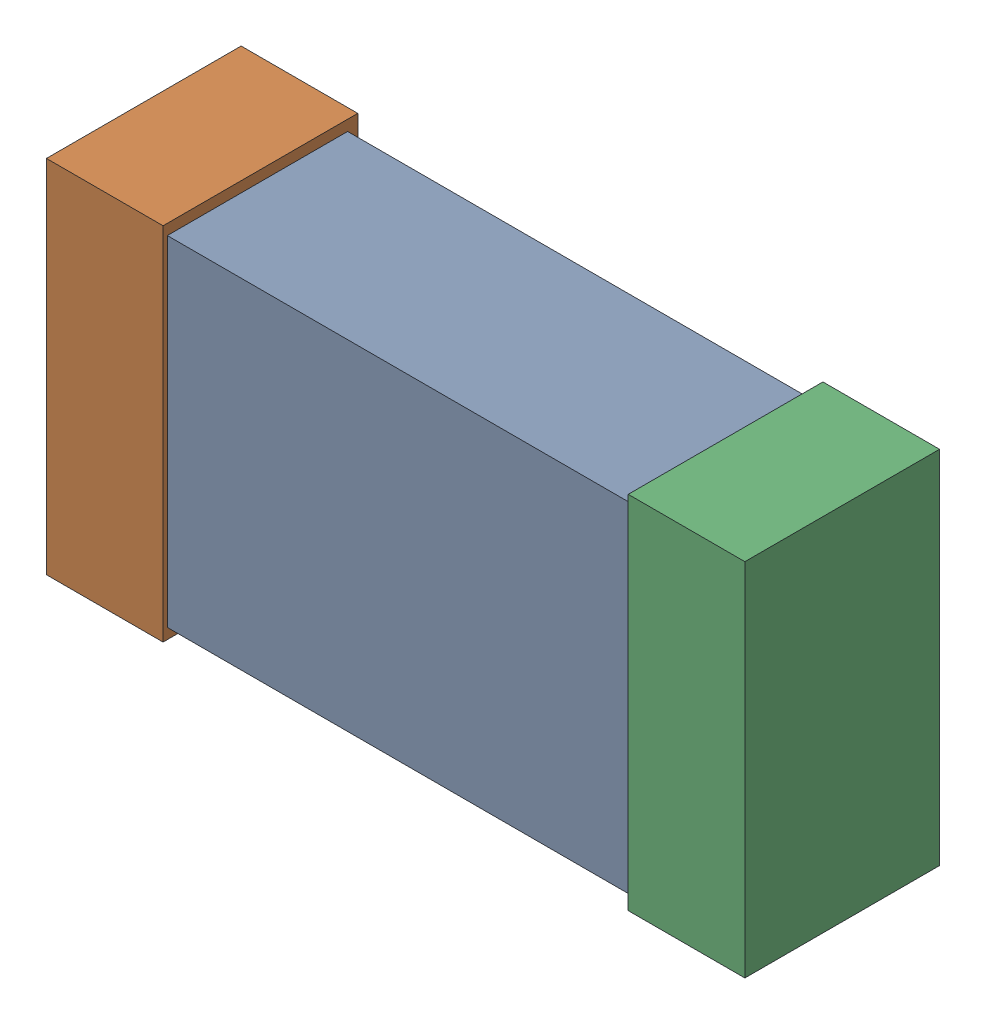
SolidWorks assembly R28, configuration Default. Lengths in mm.
Overall size (1.65 0.85 0.46).
6 component instances, 2 part files, 0 mates.
Components (placement in the parent):
- 432120720_22-1: 432120720_22 [Default] at (20.1151 16.0032 0.025) size (1.5 0.8 0.42)
  - Extruded (12)-1: Extruded (12) [Default] at origin size (1.5 0.8 0.42)
- 432120464_46-1: 432120464_46 [Default] at (19.4293 16.0032 0.001) size (0.28 0.85 0.46)
  - Extruded (11)-1: Extruded (11) [Default] at origin size (0.28 0.85 0.46)
- 432120464_47-1: 432120464_47 [Default] at (20.8008 16.0032 0.001) size (0.28 0.85 0.46)
  - Extruded (11)-1: Extruded (11) [Default] at origin size (0.28 0.85 0.46)
